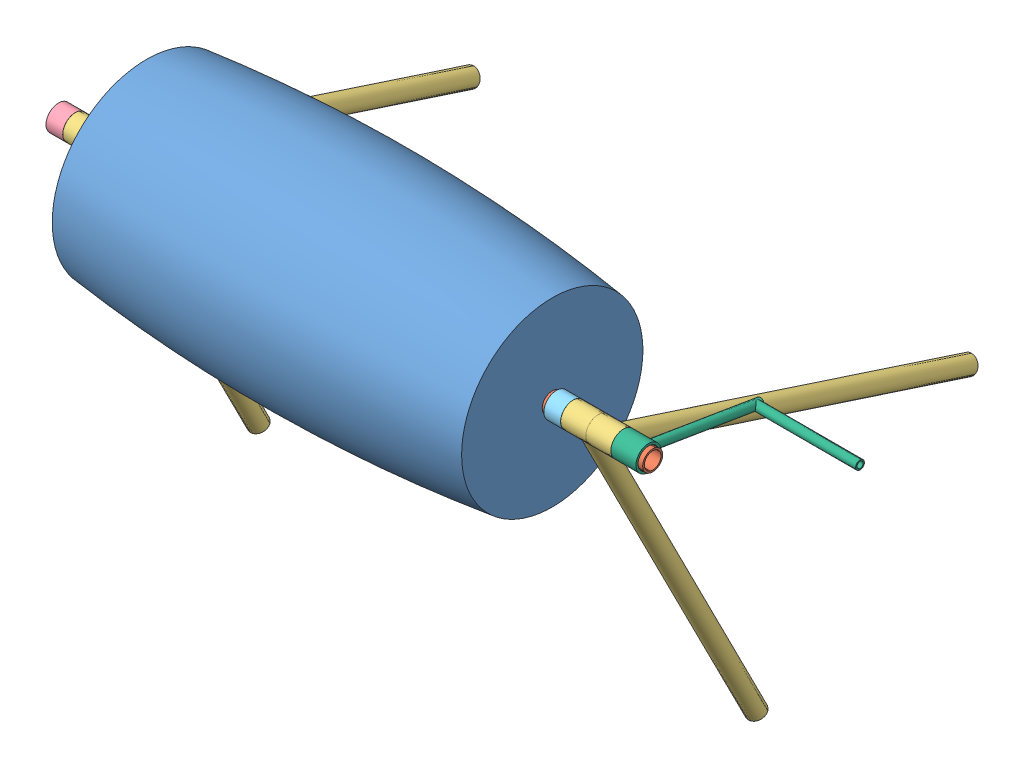
SolidWorks assembly Сборка - бетономешалка, configuration По умолчанию. Lengths in mm.
Overall size (1630 1065.96 1114.93).
10 component instances, 6 part files, 21 mates.
Components (placement in the parent):
- Бочка-1: Бочка [По умолчанию] at (-702.6645 420.2377 282.4951) size (970 500 500)
- Вал-1: Вал [По умолчанию] at (-912.6645 227.2202 282.4951) x (0 0.957192 -0.289454) z (1 0 0) size (48 48 1420)
- Ножка-1: Ножка [По умолчанию] at (407.3355 227.2202 282.4951) x (1 0 0) z (0 -0.31011 -0.950701) size (60 60 930)
- Ножка-2: Ножка [По умолчанию] at (-842.6645 227.2202 282.4951) x (1 0 0) z (0 -0.891528 -0.452966) size (60 60 930)
- Ножка-3: Ножка [По умолчанию] at (-782.6645 227.2202 282.4951) x (1 0 0) z (0 -0.31011 -0.950701) size (60 60 930)
- Ножка-4: Ножка [По умолчанию] at (347.3355 227.2202 282.4951) x (1 0 0) z (0 -0.891528 -0.452966) size (60 60 930)
- Заглушка-1: Заглушка [По умолчанию] at (-892.6645 227.2202 282.4951) x (1 0 0) z (0 -0.627908 0.778288) size (40 60 60)
- Прокладка-1: Прокладка [По умолчанию] at (-732.6645 227.2202 282.4951) size (40 60 60)
- Прокладка-2: Прокладка [По умолчанию] at (297.3355 227.2202 282.4951) x (1 0 0) z (0 0.001387 0.999999) size (40 60 60)
- Ручка-1: Ручка [По умолчанию] at (467.3355 227.2202 282.4951) x (1 0 0) z (0 -0.163124 -0.986606) size (280 60 330)
Mates (geometry in assembly coordinates):
- Концентричный1: concentric aligned: cylinder of Ножка-1 through (377.3355 227.2202 282.4951) axis (1 0 0) radius 25; cylinder of Ножка-2 through (-872.6645 227.2202 282.4951) axis (1 0 0) radius 25
- Концентричный2: concentric aligned: cylinder of Ножка-1 through (377.3355 227.2202 282.4951) axis (1 0 0) radius 25; cylinder of Ножка-3 through (-812.6645 227.2202 282.4951) axis (1 0 0) radius 25
- Концентричный3: concentric aligned: cylinder of Ножка-1 through (377.3355 227.2202 282.4951) axis (1 0 0) radius 25; cylinder of Ножка-4 through (317.3355 227.2202 282.4951) axis (1 0 0) radius 25
- Концентричный5: concentric anti-aligned: cylinder of Вал-1 through (507.3355 227.2202 282.4951) axis (-1 0 0) radius 20; cylinder of Ножка-1 through (377.3355 227.2202 282.4951) axis (1 0 0) radius 25
- Совпадение3: coincident anti-aligned: plane of Ножка-2 through (-812.6645 227.2202 282.4951) normal (1 0 0); plane of Ножка-3 through (-812.6645 227.2202 282.4951) normal (-1 0 0)
- Совпадение4: coincident anti-aligned: plane of Ножка-1 through (377.3355 227.2202 282.4951) normal (-1 0 0); plane of Ножка-4 through (377.3355 227.2202 282.4951) normal (1 0 0)
- Угол1: planar angle = 0.785398 rad aligned: plane of Ножка-3 through (-782.6645 -51.8785 -573.1356) normal (0 -0.31011 -0.950701); plane of Ножка-2 through (-842.6645 -575.1546 -125.1746) normal (0 -0.891528 -0.452966)
- Угол3: planar angle = 0.785398 rad aligned: plane of Ножка-4 through (347.3355 -575.1546 -125.1746) normal (0 -0.891528 -0.452966); plane of Ножка-1 through (407.3355 -51.8785 -573.1356) normal (0 -0.31011 -0.950701)
- Концентричный6: concentric aligned: cylinder of Бочка-1 through (267.3355 227.2202 282.4951) axis (-1 0 0) radius 24; cylinder of Вал-1 through (507.3355 227.2202 282.4951) axis (-1 0 0) radius 24
- Концентричный7: concentric aligned: cylinder of Ножка-3 through (-812.6645 227.2202 282.4951) axis (1 0 0) radius 25; cylinder of Заглушка-1 through (-912.6645 227.2202 282.4951) axis (1 0 0) radius 25
- Совпадение7: coincident anti-aligned: plane of Ножка-2 through (-872.6645 227.2202 282.4951) normal (-1 0 0); plane of Заглушка-1 through (-872.6645 227.2202 282.4951) normal (1 0 0)
- Совпадение8: coincident aligned: plane of Вал-1 through (-912.6645 227.2202 282.4951) normal (-1 0 0); plane of Заглушка-1 through (-912.6645 227.2202 282.4951) normal (-1 0 0)
- Совпадение9: coincident anti-aligned: plane of Ножка-3 through (-752.6645 227.2202 282.4951) normal (1 0 0); plane of Прокладка-1 through (-752.6645 227.2202 282.4951) normal (-1 0 0)
- Концентричный8: concentric anti-aligned: cylinder of Вал-1 through (507.3355 227.2202 282.4951) axis (-1 0 0) radius 24; cylinder of Прокладка-1 through (-752.6645 227.2202 282.4951) axis (1 0 0) radius 25
- Расстояние1: distance = 10 mm anti-aligned: plane of Бочка-1 through (-702.6645 442.1582 282.4951) normal (-1 0 0); plane of Прокладка-1 through (-712.6645 227.2202 282.4951) normal (1 0 0)
- Концентричный9: concentric anti-aligned: cylinder of Вал-1 through (507.3355 227.2202 282.4951) axis (-1 0 0) radius 24; cylinder of Прокладка-2 through (277.3355 227.2202 282.4951) axis (1 0 0) radius 25
- Совпадение11: coincident anti-aligned: plane of Ножка-4 through (317.3355 227.2202 282.4951) normal (-1 0 0); plane of Прокладка-2 through (317.3355 227.2202 282.4951) normal (1 0 0)
- Расстояние2: distance = 10 mm anti-aligned: plane of Прокладка-2 through (277.3355 227.2202 282.4951) normal (-1 0 0); plane of Бочка-1 through (267.3355 227.2202 282.4951) normal (1 0 0)
- Концентричный10: concentric anti-aligned: cylinder of Вал-1 through (507.3355 227.2202 282.4951) axis (-1 0 0) radius 24; cylinder of Ручка-1 through (437.3355 227.2202 282.4951) axis (1 0 0) radius 25
- Параллельность3: parallel aligned: cylinder of Ножка-2 through (-842.6645 -575.1546 -125.1746) axis (0 0.891528 0.452966) radius 21; cylinder of Ножка-4 through (347.3355 -575.1546 -125.1746) axis (0 0.891528 0.452966) radius 21
- Совпадение14: coincident anti-aligned: plane of Ножка-1 through (437.3355 227.2202 282.4951) normal (1 0 0); plane of Ручка-1 through (437.3355 227.2202 282.4951) normal (-1 0 0)
